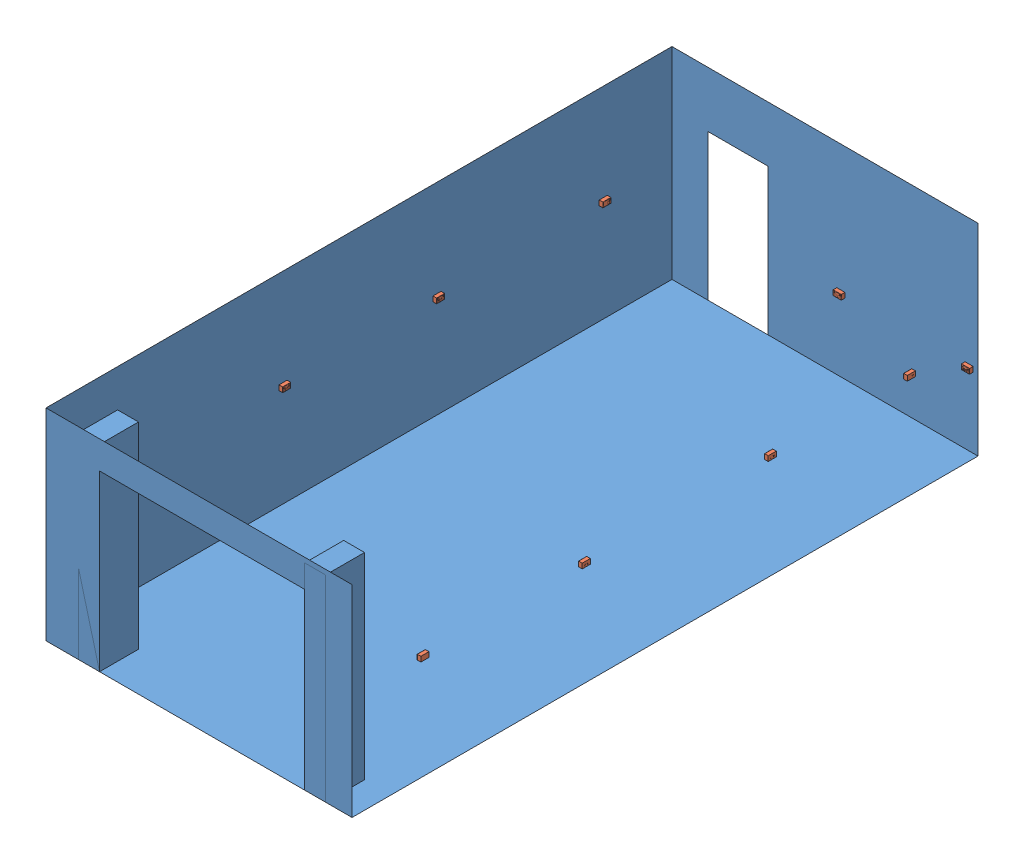
SolidWorks assembly Workshop with fittings, configuration Default. Lengths in mm.
Overall size (6672.45 3882.52 12593.15).
11 component instances, 2 part files, 30 mates.
Components (placement in the parent):
- Workshop-1: Workshop [Default] at (-2272.4477 -1992.5143 4533.144) size (4400 2900 9000)
- Aus Power Point-1: Aus Power Point [Double Switch] at (1941.5523 -982.5143 -4424.856) x (1 0 0) z (0 1 0) size (116 59.04 72)
- Aus Power Point-3: Aus Power Point [Double Switch] at (97.5523 -982.5143 -4424.856) x (1 0 0) z (0 1 0) size (116 59.04 72)
- Aus Power Point-4: Aus Power Point [Double Switch] at (2085.5523 -552.5143 -3566.856) x (0 0 1) z (0 1 0) size (116 59.04 72)
- Aus Power Point-5: Aus Power Point [Double Switch] at (2085.5523 -552.5143 -1566.856) x (0 0 1) z (0 1 0) size (116 59.04 72)
- Aus Power Point-6: Aus Power Point [Single Switch] at (2085.5523 -552.5143 3427.144) x (0 0 1) z (0 1 0) size (116 59.04 72)
- Aus Power Point-7: Aus Power Point [Single Switch] at (-2230.4477 -552.5143 -3420.856) x (0 0 -1) z (0 1 0) size (116 59.04 72)
- Aus Power Point-8: Aus Power Point [Double Switch] at (-2230.4477 -552.5143 -1030.856) x (0 0 -1) z (0 1 0) size (116 59.04 72)
- Aus Power Point-9: Aus Power Point [Double Switch] at (-2230.4477 -552.5143 3593.144) x (0 0 -1) z (0 1 0) size (116 59.04 72)
- Aus Power Point-10: Aus Power Point [Double Switch] at (-2230.4477 -552.5143 1183.144) x (0 0 -1) z (0 1 0) size (116 59.04 72)
- Aus Power Point-11: Aus Power Point [Double Switch] at (2085.5523 -552.5143 1107.144) x (0 0 1) z (0 1 0) size (116 59.04 72)
Mates (geometry in assembly coordinates):
- Coincident1: coincident aligned: plane of Workshop-1 through (-2272.4477 -1992.5143 -4466.856) normal (0 0 -1); plane of Aus Power Point-1 through (1941.5523 -982.5143 -4466.856) normal (0 0 -1)
- Coincident2: coincident: point of assembly; point of Workshop-1; point of Aus Power Point-1
- Parallel1: parallel aligned: plane of Workshop-1 through (-2272.4477 -1992.5143 4533.144) normal (0 -1 0); plane of Aus Power Point-1 through (1941.5523 -982.5143 -4424.856) normal (0 -1 0)
- Coincident7: coincident aligned: plane of Workshop-1 through (-2272.4477 -1992.5143 -4466.856) normal (0 0 -1); plane of Aus Power Point-3 through (97.5523 -982.5143 -4466.856) normal (0 0 -1)
- Coincident8: coincident: point of Aus Power Point-3; point of Aus Power Point-3
- Parallel3: parallel aligned: plane of Workshop-1 through (-2272.4477 -1992.5143 4533.144) normal (0 -1 0); plane of Aus Power Point-3 through (97.5523 -982.5143 -4424.856) normal (0 -1 0)
- Coincident10: coincident aligned: plane of Workshop-1 through (2127.5523 -1992.5143 4533.144) normal (1 0 0); plane of Aus Power Point-4 through (2127.5523 -552.5143 -3566.856) normal (1 0 0)
- Parallel4: parallel aligned: plane of Workshop-1 through (-2272.4477 -1992.5143 4533.144) normal (0 -1 0); plane of Aus Power Point-4 through (2085.5523 -552.5143 -3566.856) normal (0 -1 0)
- Coincident13: coincident: point of assembly; point of Workshop-1; point of Aus Power Point-4
- Coincident14: coincident aligned: plane of Workshop-1 through (2127.5523 -1992.5143 4533.144) normal (1 0 0); plane of Aus Power Point-5 through (2127.5523 -552.5143 -1566.856) normal (1 0 0)
- Parallel5: parallel aligned: plane of Workshop-1 through (-2272.4477 -1992.5143 4533.144) normal (0 -1 0); plane of Aus Power Point-5 through (2085.5523 -552.5143 -1566.856) normal (0 -1 0)
- Coincident16: coincident: point of Aus Power Point-5; point of Aus Power Point-5
- Coincident17: coincident aligned: plane of Workshop-1 through (2127.5523 -1992.5143 4533.144) normal (1 0 0); plane of Aus Power Point-6 through (2127.5523 -552.5143 3427.144) normal (1 0 0)
- Parallel6: parallel aligned: plane of Workshop-1 through (-2272.4477 -1992.5143 4533.144) normal (0 -1 0); plane of Aus Power Point-6 through (2085.5523 -552.5143 3427.144) normal (0 -1 0)
- Coincident19: coincident: point of Aus Power Point-6; point of Aus Power Point-6
- Coincident20: coincident aligned: plane of Workshop-1 through (-2272.4477 -1992.5143 4533.144) normal (-1 0 0); plane of Aus Power Point-7 through (-2272.4477 -552.5143 -3420.856) normal (-1 0 0)
- Parallel7: parallel aligned: plane of Workshop-1 through (-2272.4477 -1992.5143 4533.144) normal (0 -1 0); plane of Aus Power Point-7 through (-2230.4477 -552.5143 -3420.856) normal (0 -1 0)
- Coincident22: coincident: unknown of Workshop-1; unknown of Aus Power Point-7
- Coincident23: coincident aligned: plane of Workshop-1 through (-2272.4477 -1992.5143 4533.144) normal (-1 0 0); plane of Aus Power Point-8 through (-2272.4477 -552.5143 -1030.856) normal (-1 0 0)
- Parallel8: parallel aligned: plane of Workshop-1 through (-2272.4477 -1992.5143 4533.144) normal (0 -1 0); plane of Aus Power Point-8 through (-2230.4477 -552.5143 -1030.856) normal (0 -1 0)
- Coincident25: coincident: point of assembly; point of Workshop-1; point of Aus Power Point-8
- Coincident26: coincident aligned: plane of Workshop-1 through (-2272.4477 -1992.5143 4533.144) normal (-1 0 0); plane of Aus Power Point-9 through (-2272.4477 -552.5143 3593.144) normal (-1 0 0)
- Parallel9: parallel aligned: plane of Workshop-1 through (-2272.4477 -1992.5143 4533.144) normal (0 -1 0); plane of Aus Power Point-9 through (-2230.4477 -552.5143 3593.144) normal (0 -1 0)
- Coincident28: coincident: point of assembly; point of Workshop-1; point of Aus Power Point-9
- Coincident29: coincident: point of assembly; point of Workshop-1; point of Aus Power Point-10
- Parallel10: parallel anti-aligned: plane of Workshop-1 through (-2272.4477 -1992.5143 4533.144) normal (0 -1 0); plane of Aus Power Point-10 through (-2230.4477 -480.5143 1067.144) normal (0 1 0)
- Coincident31: coincident aligned: plane of Workshop-1 through (-2272.4477 -1992.5143 4533.144) normal (-1 0 0); plane of Aus Power Point-10 through (-2272.4477 -552.5143 1183.144) normal (-1 0 0)
- Coincident32: coincident aligned: plane of Workshop-1 through (2127.5523 -1992.5143 4533.144) normal (1 0 0); plane of Aus Power Point-11 through (2127.5523 -552.5143 1107.144) normal (1 0 0)
- Parallel11: parallel anti-aligned: plane of Workshop-1 through (-2272.4477 -1992.5143 4533.144) normal (0 -1 0); plane of Aus Power Point-11 through (2085.5523 -480.5143 1223.144) normal (0 1 0)
- Coincident34: coincident: point of assembly; point of Workshop-1; point of Aus Power Point-11
